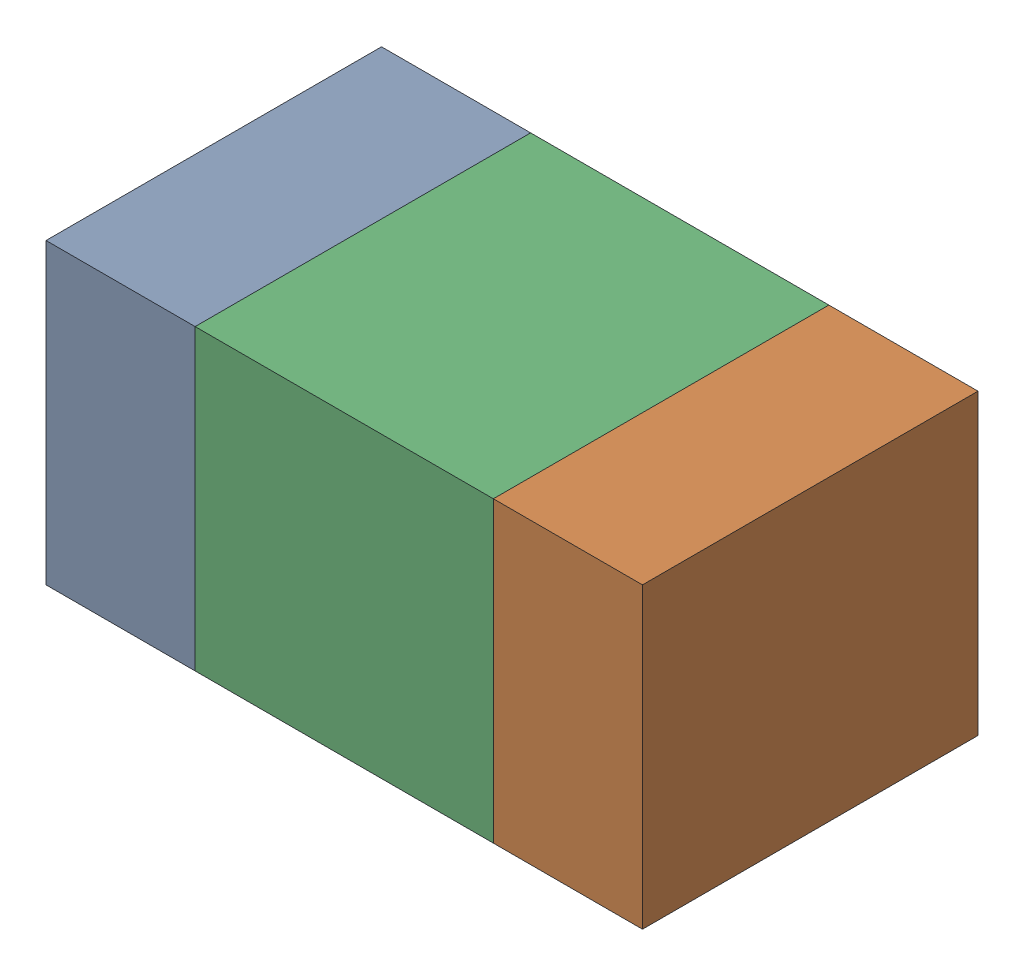
SolidWorks assembly C40, configuration ﾃﾞﾌｫﾙﾄ. Lengths in mm.
Overall size (1.6 0.8 0.9).
6 component instances, 2 part files, 0 mates.
Components (placement in the parent):
- 689259744-1: 689259744 [ﾃﾞﾌｫﾙﾄ] at (69.4001 16.7501 0) size (0.4 0.8 0.9)
  - Extruded_4-1: Extruded_4 [ﾃﾞﾌｫﾙﾄ] at origin size (0.4 0.8 0.9)
- 689259744-2: 689259744 [ﾃﾞﾌｫﾙﾄ] at (70.6001 16.7501 0) size (0.4 0.8 0.9)
  - Extruded_4-1: Extruded_4 [ﾃﾞﾌｫﾙﾄ] at origin size (0.4 0.8 0.9)
- 689259608-1: 689259608 [ﾃﾞﾌｫﾙﾄ] at (70 16.7501 0) size (0.8 0.8 0.9)
  - Extruded_3-1: Extruded_3 [ﾃﾞﾌｫﾙﾄ] at origin size (0.8 0.8 0.9)
